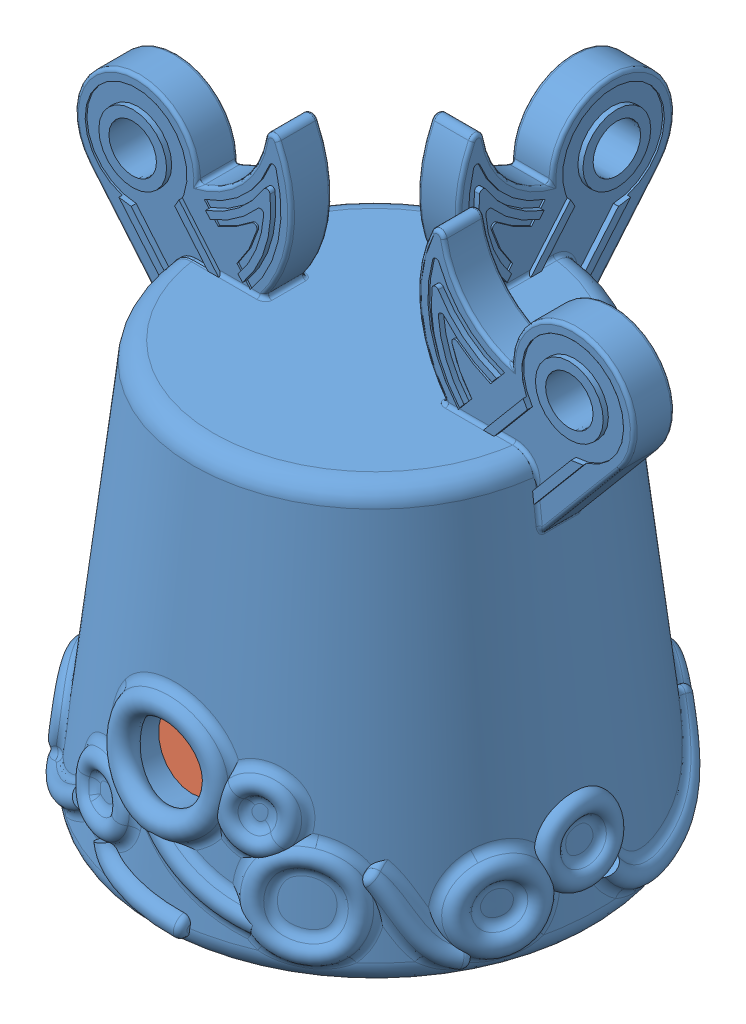
SolidWorks assembly guardian_head, configuration 默认. Lengths in mm.
Overall size (82.29 81.26 75.5).
6 component instances, 6 part files, 16 mates.
Components (placement in the parent):
- head-1: head [默认] at origin size (82.29 81.26 75.5)
- oled_transparent-1: oled_transparent [默认] at (0 2.7538 24.4424) x (0 0.99369 -0.112163) z (0 0.112163 0.99369) size (42.04 41.21 30.66)
- servo_motor(mini)-1: servo_motor(mini) [默认] at (-22.92 -8.7117 9.93) x (0 0 1) z (0 1 0) size (23.1 19.82 8.42)
- laser-1: laser [默认] at (0 -8.7117 8.86) x (0 -1 0) z (0 0 1) size (4 4 16.6)
- mini_handle-1: mini_handle [默认] at (-3.1 -8.7117 13.94) x (0 0 1) z (1 0 0) size (10.48 5.44 3.12)
- servo_motor_holder2-1: servo_motor_holder2 [默认] at (-15.8002 -14.7 10.1997) x (0.532074 0 0.846698) z (-0.846698 0 0.532074) size (29.51 1.5 4.4)
Mates (geometry in assembly coordinates):
- 平行1: parallel: plane of head-1 through (0 27.8107 0) normal (0 -1 0); line of oled_transparent-1 through (-13.61 -18.0752 27.3168) axis (1 0 0)
- 宽度2: width aligned: plane of oled_transparent-1 through (-13.61 -18.0752 27.3168) normal (-1 0 0); plane of head-1 through (13.61 -18.0752 27.3168) normal (1 0 0); plane of oled_transparent-1 through (14 -18.7765 25.3832) normal (-1 0 0); plane of head-1 through (-14 23.9522 20.5602) normal (1 0 0)
- 重合4: coincident anti-aligned: plane of head-1 through (0 2.8172 24.9586) normal (0 -0.112163 -0.99369); plane of oled_transparent-1 through (0 2.8122 24.9591) normal (0 0.112163 0.99369)
- 宽度3: width anti-aligned: plane of oled_transparent-1 through (-13.61 23.6995 22.6015) normal (0 0.99369 -0.112163); plane of head-1 through (-13.61 -18.0752 27.3168) normal (0 -0.99369 0.112163); plane of oled_transparent-1 through (14 23.9522 20.5602) normal (0 -0.99369 0.112163); plane of head-1 through (-14 -18.7765 25.3832) normal (0 0.99369 -0.112163)
- 平行7: parallel anti-aligned: plane of head-1 through (0 27.8107 0) normal (0 -1 0); plane of servo_motor(mini)-1 through (-11.92 -4.5017 1.82) normal (0 1 0)
- 重合15: coincident anti-aligned: plane of servo_motor(mini)-1 through (-3.1 -8.7117 13.94) normal (1 0 0); plane of mini_handle-1 through (-3.1 -8.7117 13.94) normal (-1 0 0)
- 同心3: concentric anti-aligned: cylinder of servo_motor(mini)-1 through (-3.1 -8.7117 13.94) axis (-1 0 0) radius 1.89; cylinder of mini_handle-1 through (-5.1 -8.7117 13.94) axis (1 0 0) radius 1.95
- 相切4: tangent anti-aligned: cylinder of laser-1 through (0 -8.7117 16.66) axis (0 0 -1) radius 2; plane of mini_handle-1 through (-2 -8.7117 13.94) normal (1 0 0)
- 相切5: tangent aligned: plane of laser-1 through (0 -8.7117 16.66) normal (0 0 1); cylinder of mini_handle-1 through (-2 -8.7117 13.94) axis (-1 0 0) radius 2.72
- 宽度5: width anti-aligned: plane of laser-1 through (0.9 -10.4977 3.36) normal (0 -1 0); plane of mini_handle-1 through (0.9 -6.9256 3.36) normal (0 1 0); plane of laser-1 through (-2 -6.9817 13.94) normal (0 1 0); plane of mini_handle-1 through (-2 -10.4417 13.94) normal (0 -1 0)
- 平行8: parallel anti-aligned: line of servo_motor(mini)-1 through (-8.48 -12.9217 13.94) axis (0 0 -1); line of laser-1 through (0.9 -10.4977 3.36) axis (0 0 1)
- 同心7: concentric anti-aligned: circle of laser-1
- 相切6: tangent anti-aligned: plane of head-1 through (-6.58 7.0504 7.46) normal (0 0 1); cylinder of servo_motor(mini)-1 through (-5.87 -8.7117 9.81) axis (-1 0 0) radius 2.35
- 同心12: concentric aligned: cylinder of head-1 through (-22.48 -13.2 -0.43) axis (0 -1 0) radius 0.55; cylinder of servo_motor_holder2-1 through (-22.4804 -13.2 -0.4306) axis (0 -1 0) radius 0.5
- 同心15: concentric aligned: cylinder of head-1 through (-9.12 -13.2 20.83) axis (0 -1 0) radius 0.55; cylinder of servo_motor_holder2-1 through (-9.12 -13.2 20.83) axis (0 -1 0) radius 0.5
- 重合16: coincident anti-aligned: plane of head-1 through (-15.8 -13.2 10.2) normal (0 -1 0); plane of servo_motor_holder2-1 through (-22.4804 -13.2 -0.4306) normal (0 1 0)
